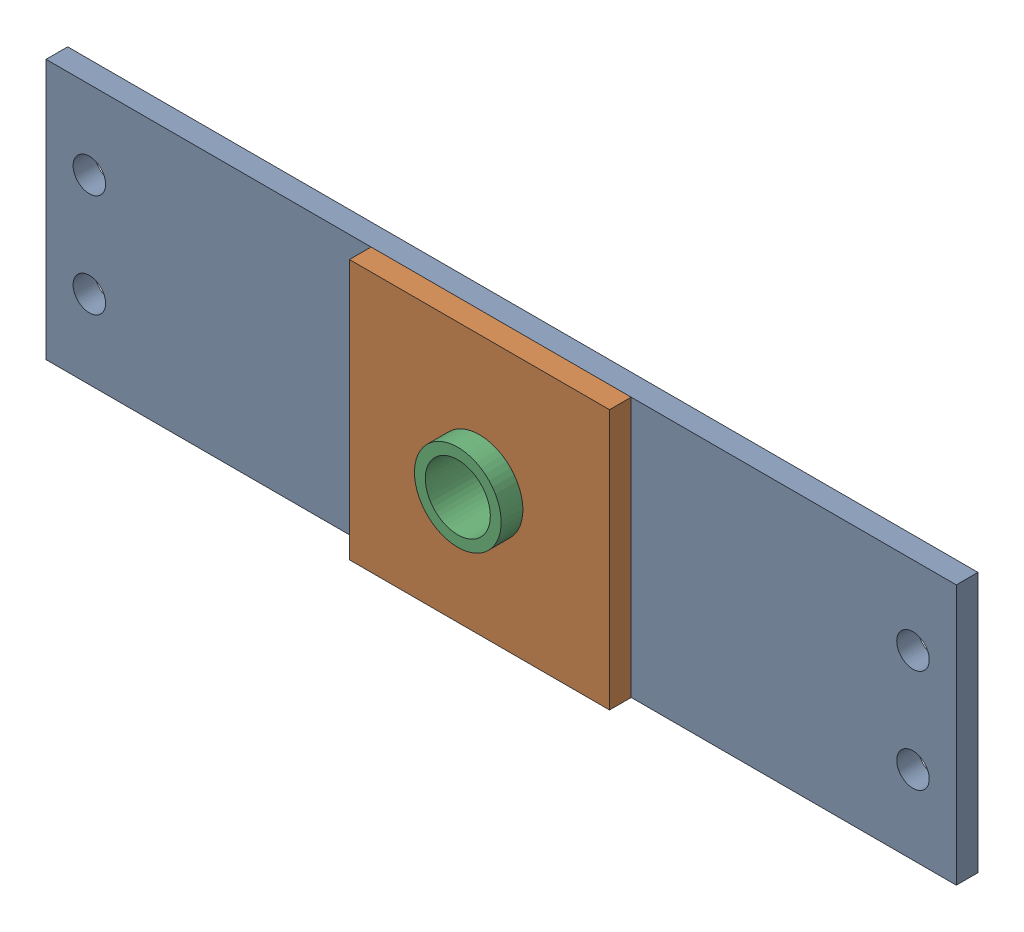
SolidWorks assembly Base Plate Ass, configuration Default. Lengths in mm.
Overall size (533.4 152.4 38.1).
3 component instances, 3 part files, 0 mates.
Components (placement in the parent):
- Base plate update-1: Base plate update [Default] at (-316.9216 -80.8539 23.313) size (533.4 152.4 12.7)
- Base Plate Support-1: Base Plate Support [Default] at (-126.4216 -80.8539 36.013) size (152.4 152.4 12.7)
- 01-109-00-0-1: 01-109-00-0 [Default] at (-50.2216 -4.6539 23.313) x (1 0 0) z (0 -1 0) size (50.8 38.1 50.8)
